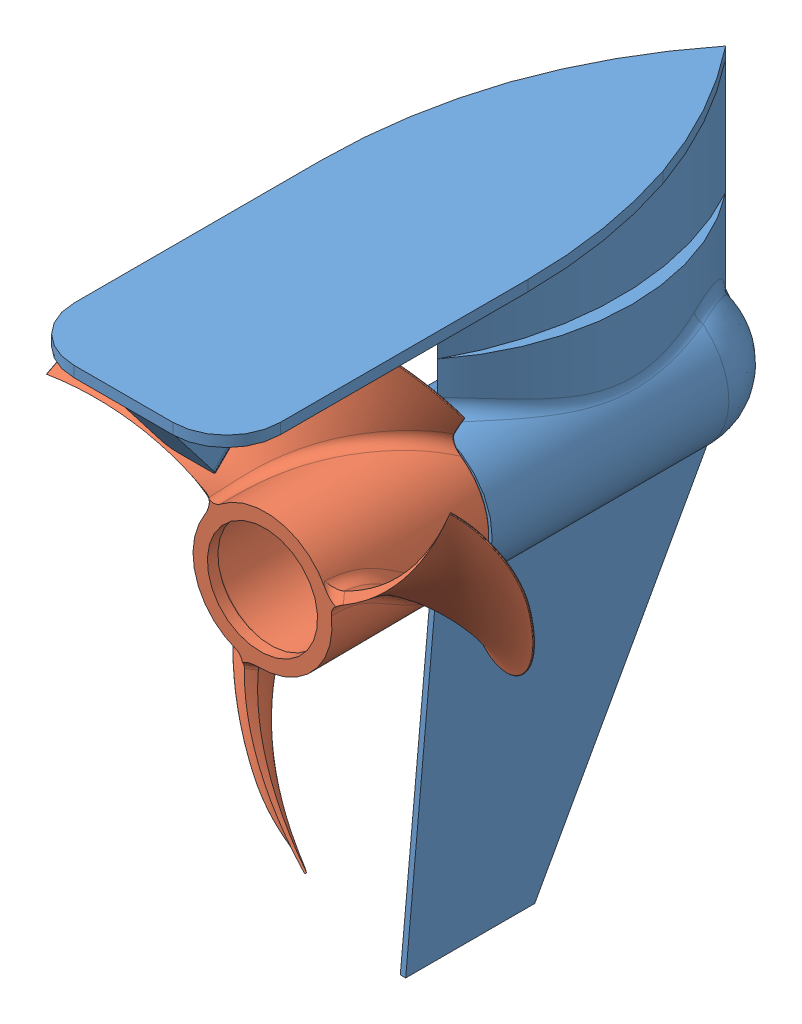
SolidWorks assembly Сборка1, configuration По умолчанию. Lengths in mm.
Overall size (241.48 304.99 290.64).
2 component instances, 2 part files, 0 mates.
Components (placement in the parent):
- Reduktor_Veterok-1: Reduktor_Veterok [По умолчанию] at (-74.6887 60.2993 27.318) size (96 300.82 290.64)
- V12_340_0_75_3-2: V12_340_0_75_3 [По умолчанию] at (-74.158 61.6131 100.2423) x (0.260626 -0.965399 0.008908) z (-0.025477 -0.016101 -0.999546) size (197.15 194.73 84.96)
